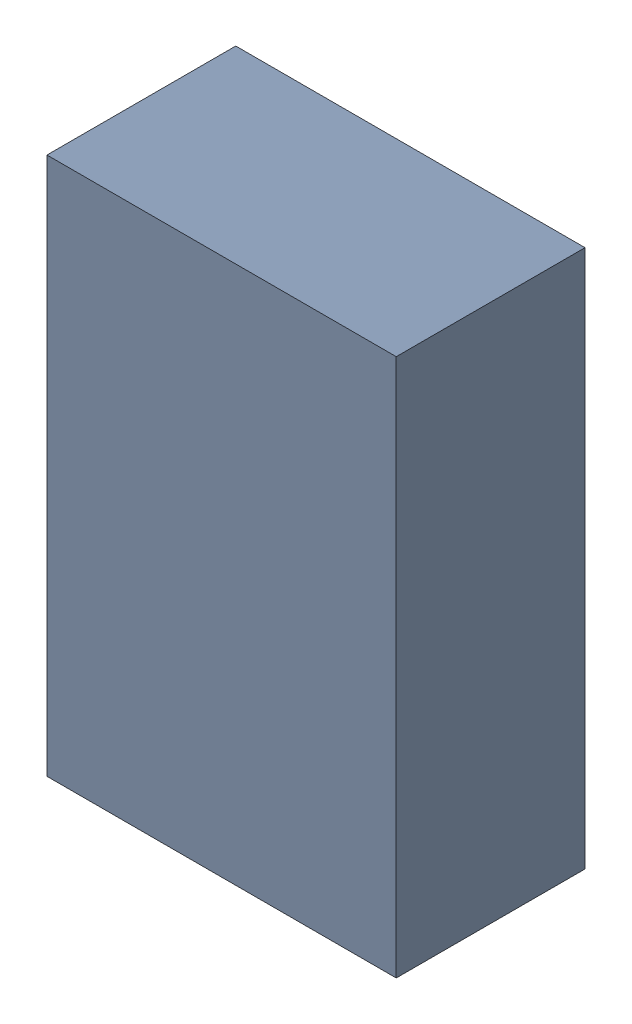
SolidWorks assembly U3, configuration Default. Lengths in mm.
Overall size (1.11 1.71 0.61).
4 component instances, 2 part files, 0 mates.
Components (placement in the parent):
- 1737251728-1: 1737251728 [Default] at (7.275 49 -2.244) size (1.11 1.71 0.6)
  - Extruded-23-1: Extruded-23 [Default] at origin size (1.11 1.71 0.6)
- 1737316080-1: 1737316080 [Default] at (7.2751 48.3751 -2.244) x (0 1 0) z (0 0 -1) size (0.4 0.4 0.01)
  - Cylinder-24-1: Cylinder-24 [Default] at origin size (0.4 0.4 0.01)
